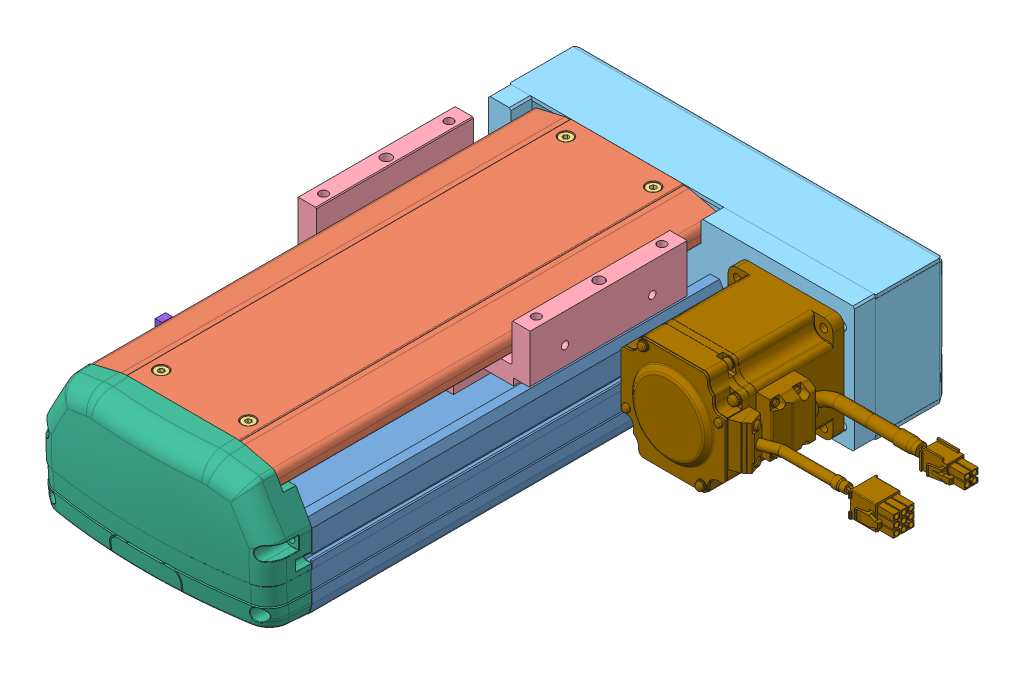
SolidWorks assembly S13-BR-200W, configuration 默认. Lengths in mm.
Overall size (306.2 78 318.96).
14 component instances, 9 part files, 43 mates.
Components (placement in the parent):
- S13-BL底座^S13-BR-200W-1: S13-BL底座^S13-BR-200W [默认] at origin size (135 48 259) (virtual)
- S13-BL上盖^S13-BR-200W-1: S13-BL上盖^S13-BR-200W [默认] at (0 60.45 115.5) size (109 12.5 255) (virtual)
- 内六角圆柱头螺钉M4×8[GB／T70．1-2000]^S13-BR-200W-1: 内六角圆柱头螺钉M4×8[GB／T70．1-2000]^S13-BR-200W [默认] at (-25 72.65 -2) x (0 -1 0) z (-0.993621 0 -0.11277) size (12 7 7) (virtual)
- 内六角圆柱头螺钉M4×8[GB／T70．1-2000]^S13-BR-200W-2: 内六角圆柱头螺钉M4×8[GB／T70．1-2000]^S13-BR-200W [默认] at (25 72.65 -2) x (0 -1 0) z (0.295931 0 -0.955209) size (12 7 7) (virtual)
- 内六角圆柱头螺钉M4×8[GB／T70．1-2000]^S13-BR-200W-3: 内六角圆柱头螺钉M4×8[GB／T70．1-2000]^S13-BR-200W [默认] at (-25 72.65 230) x (0 -1 0) z (0.881053 0 0.473018) size (12 7 7) (virtual)
- 内六角圆柱头螺钉M4×8[GB／T70．1-2000]^S13-BR-200W-4: 内六角圆柱头螺钉M4×8[GB／T70．1-2000]^S13-BR-200W [默认] at (25 72.65 230) x (0 -1 0) z (0.809751 0 0.586773) size (12 7 7) (virtual)
- S13-BC滑座^S13-BR-200W-1: S13-BC滑座^S13-BR-200W [默认] at (-1.3936 35.7784 20) size (133 62 90) (virtual)
- 复件 S13-14-BR电机板罩壳^S13-BR-200W-2: 复件 S13-14-BR电机板罩壳^S13-BR-200W [默认] at (34.6396 24.1 343.3649) x (1 0 0) z (0 1 0) size (210.56 52 72) (virtual)
- 复件 13-14塑胶端盖 ^S13-BR-200W-1: 复件 13-14塑胶端盖 ^S13-BR-200W [默认] at (0 1 256) x (-1 0 0) z (0 0 -1) size (134.5 73.26 31.04) (virtual)
- 复件 外置感应片ST14-17^S13-BR-200W-1: 复件 外置感应片ST14-17^S13-BR-200W [默认] at (-67.5 55 65) x (0 0 1) z (-1 0 0) size (70 30.4 7.7) (virtual)
- 复件 光电开关EE-SX672^S13-BR-200W-1: 复件 光电开关EE-SX672^S13-BR-200W [默认] at (-67.5 19.7 49) x (0 0 1) z (-1 0 0) size (26 25 13) (virtual)
- 复件 光电开关EE-SX672^S13-BR-200W-2: 复件 光电开关EE-SX672^S13-BR-200W [默认] at (-67.5 19.7 75) x (0 0 1) z (-1 0 0) size (26 25 13) (virtual)
- 复件 光电开关EE-SX672^S13-BR-200W-3: 复件 光电开关EE-SX672^S13-BR-200W [默认] at (-67.5 19.7 172) x (0 0 1) z (-1 0 0) size (26 25 13) (virtual)
- 复件 松下200W电机MHMF022L1U22^S13-BR-200W-1: 复件 松下200W电机MHMF022L1U22^S13-BR-200W [默认] at (106.5 35.4 0) x (0 0 -1) z (0 -1 0) size (101 149.2 60) (virtual)
Mates (geometry in assembly coordinates):
- 重合169: coincident: plane of S13-BL上盖^S13-BR-200W-1 through (-25 68.65 -2) normal (0 1 0); plane of 内六角圆柱头螺钉M4×8[GB／T70．1-2000]^S13-BR-200W-1 through (-25.3947 68.65 1.4777) normal (0 -1 0)
- 同心160: concentric: cylinder of 内六角圆柱头螺钉M4×8[GB／T70．1-2000]^S13-BR-200W-1 through (-25 72.65 -2) axis (0 1 0) radius 3.5; cylinder of S13-BL上盖^S13-BR-200W-1 through (-25 68.65 -2) axis (0 1 0) radius 4
- 同心161: concentric: cylinder of 内六角圆柱头螺钉M4×8[GB／T70．1-2000]^S13-BR-200W-2 through (25 72.65 -2) axis (0 1 0) radius 3.5; cylinder of S13-BL上盖^S13-BR-200W-1 through (25 68.65 -2) axis (0 1 0) radius 4
- 重合171: coincident: plane of S13-BL上盖^S13-BR-200W-1 through (25 68.65 -2) normal (0 1 0); circle of 内六角圆柱头螺钉M4×8[GB／T70．1-2000]^S13-BR-200W-2
- 重合189: coincident: plane of S13-BL上盖^S13-BR-200W-1 through (25 68.65 230) normal (0 1 0); plane of 内六角圆柱头螺钉M4×8[GB／T70．1-2000]^S13-BR-200W-4 through (27.0537 68.65 227.1659) normal (0 -1 0)
- 同心192: concentric: cylinder of S13-BL上盖^S13-BR-200W-1 through (25 68.65 230) axis (0 1 0) radius 4; cylinder of 内六角圆柱头螺钉M4×8[GB／T70．1-2000]^S13-BR-200W-4 through (25 72.65 230) axis (0 1 0) radius 2
- 重合190: coincident: plane of S13-BL上盖^S13-BR-200W-1 through (-25 68.65 230) normal (0 1 0); plane of 内六角圆柱头螺钉M4×8[GB／T70．1-2000]^S13-BR-200W-3 through (-23.3444 68.65 226.9163) normal (0 -1 0)
- 同心193: concentric: cylinder of S13-BL上盖^S13-BR-200W-1 through (-25 68.65 230) axis (0 1 0) radius 4; cylinder of 内六角圆柱头螺钉M4×8[GB／T70．1-2000]^S13-BR-200W-3 through (-25 72.65 230) axis (0 1 0) radius 2
- 距离15: distance = 78 mm: plane of S13-BC滑座^S13-BR-200W-1 through (66.5 78 20) normal (0 1 0); plane of S13-BL底座^S13-BR-200W-1 through (-65.3076 0 259) normal (0 -1 0)
- 重合205: coincident: plane of S13-BL底座^S13-BR-200W-1 through (0 0 0) normal (1 0 0); plane of S13-BL上盖^S13-BR-200W-1 through (0 60.45 115.5) normal (1 0 0)
- 距离37: distance = 12 mm: plane of S13-BL底座^S13-BR-200W-1 through (-56.7 26.5 0) normal (0 0 -1); plane of S13-BL上盖^S13-BR-200W-1 through (50.5 64.7864 -12) normal (0 0 -1)
- 重合238: coincident: plane of S13-BL底座^S13-BR-200W-1 through (0 0 0) normal (0 0 1); plane of assembly through (0 0 0) normal (0 0 1)
- 重合239: coincident: plane of S13-BL底座^S13-BR-200W-1 through (0 0 0) normal (0 1 0); plane of assembly through (0 0 0) normal (0 1 0)
- 重合240: coincident: plane of S13-BL底座^S13-BR-200W-1 through (0 0 0) normal (1 0 0); plane of assembly through (0 0 0) normal (1 0 0)
- 宽度2: width: plane of S13-BL底座^S13-BR-200W-1 through (67.5 43.6699 259) normal (1 0 0); plane of S13-BL底座^S13-BR-200W-1 through (-67.5 43.6699 259) normal (-1 0 0); plane of S13-BC滑座^S13-BR-200W-1 through (-66.5 16 113.7559) normal (-1 0 0); plane of S13-BC滑座^S13-BR-200W-1 through (66.5 16 116.3186) normal (1 0 0)
- 重合265: coincident: plane of S13-BL底座^S13-BR-200W-1 through (-56.7 26.5 0) normal (0 0 -1); plane of 复件 S13-14-BR电机板罩壳^S13-BR-200W-2 through (37.5 37 0) normal (0 0 1)
- 重合266: coincident: plane of S13-BL底座^S13-BR-200W-1 through (-67.5 43.6699 259) normal (-1 0 0); plane of 复件 S13-14-BR电机板罩壳^S13-BR-200W-2 through (-67.5 1 0) normal (-1 0 0)
- 距离47: distance = 1 mm: plane of 复件 S13-14-BR电机板罩壳^S13-BR-200W-2 through (-67.5 1 0) normal (0 -1 0); plane of S13-BL底座^S13-BR-200W-1 through (-65.3076 0 259) normal (0 -1 0)
- 重合269: coincident: plane of S13-BL上盖^S13-BR-200W-1 through (-54 60.45 243) normal (0 -1 0); plane of 复件 S13-14-BR电机板罩壳^S13-BR-200W-2 through (-54.5 60.45 -12) normal (0 1 0)
- 同心202: concentric: cylinder of S13-BL底座^S13-BR-200W-1 through (62.5 39.5 259) axis (0 0 -1) radius 1.4999; cylinder of 复件 13-14塑胶端盖 ^S13-BR-200W-1 through (62.5 39.5 236) axis (0 0 -1) radius 2.1
- 同心203: concentric: cylinder of S13-BL底座^S13-BR-200W-1 through (-62.5 39.5 259) axis (0 0 -1) radius 1.5; cylinder of 复件 13-14塑胶端盖 ^S13-BR-200W-1 through (-62.5 39.5 236) axis (0 0 -1) radius 2.1
- 重合270: coincident: plane of S13-BL底座^S13-BR-200W-1 through (-73.9407 48 236) normal (0 0 1); plane of 复件 13-14塑胶端盖 ^S13-BR-200W-1 through (0 1 236) normal (0 0 1)
- 重合271: coincident: plane of S13-BC滑座^S13-BR-200W-1 through (-66.5 16 113.7559) normal (-1 0 0); plane of 复件 外置感应片ST14-17^S13-BR-200W-1 through (-66.5 55 65) normal (1 0 0)
- 同心204: concentric: cylinder of S13-BC滑座^S13-BR-200W-1 through (-67 61 94) axis (-1 0 0) radius 2.1; cylinder of 复件 外置感应片ST14-17^S13-BR-200W-1 through (-67.5 61 94) axis (-1 0 0) radius 2.55
- 同心205: concentric: cylinder of S13-BC滑座^S13-BR-200W-1 through (-67 61 44) axis (-1 0 0) radius 2.1; cylinder of 复件 外置感应片ST14-17^S13-BR-200W-1 through (-67.5 61 44) axis (-1 0 0) radius 2.55
- 重合272: coincident: plane of S13-BL底座^S13-BR-200W-1 through (-67.5 43.6699 259) normal (-1 0 0); plane of 复件 光电开关EE-SX672^S13-BR-200W-1 through (-67.5 44.7 49) normal (1 0 0)
- 距离49: distance = 19.7 mm: plane of 复件 光电开关EE-SX672^S13-BR-200W-1 through (-80.5 19.7 49) normal (0 -1 0); plane of S13-BL底座^S13-BR-200W-1 through (-65.3076 0 259) normal (0 -1 0)
- 距离50: distance = 53 mm: plane of 复件 光电开关EE-SX672^S13-BR-200W-1 through (-80.5 19.7 53) normal (0 0 -1); plane of S13-BL底座^S13-BR-200W-1 through (-56.7 26.5 0) normal (0 0 -1)
- 重合275: coincident: plane of 复件 光电开关EE-SX672^S13-BR-200W-1 through (-80.5 44.7 49) normal (-1 0 0); plane of 复件 光电开关EE-SX672^S13-BR-200W-2 through (-80.5 44.7 75) normal (-1 0 0)
- 重合276: coincident: plane of 复件 光电开关EE-SX672^S13-BR-200W-1 through (-70 32.7 65) normal (0 0 1); plane of 复件 光电开关EE-SX672^S13-BR-200W-2 through (-70 32.7 65) normal (0 0 -1)
- 重合277: coincident: plane of 复件 光电开关EE-SX672^S13-BR-200W-1 through (-80.5 19.7 49) normal (0 -1 0); plane of 复件 光电开关EE-SX672^S13-BR-200W-2 through (-80.5 19.7 75) normal (0 -1 0)
- 宽度4: width: plane of 复件 光电开关EE-SX672^S13-BR-200W-2 through (-80.5 19.7 79) normal (0 0 -1); plane of 复件 光电开关EE-SX672^S13-BR-200W-1 through (-80.5 19.7 59) normal (0 0 1); plane of 复件 外置感应片ST14-17^S13-BR-200W-1 through (-74.2 37.6 61.5) normal (0 0 -1); plane of 复件 外置感应片ST14-17^S13-BR-200W-1 through (-74.2 53 76.5) normal (0 0 1)
- 重合278: coincident: plane of 复件 光电开关EE-SX672^S13-BR-200W-2 through (-80.5 44.7 75) normal (-1 0 0); plane of 复件 光电开关EE-SX672^S13-BR-200W-3 through (-80.5 44.7 172) normal (-1 0 0)
- 重合279: coincident: plane of 复件 光电开关EE-SX672^S13-BR-200W-2 through (-80.5 19.7 75) normal (0 -1 0); plane of 复件 光电开关EE-SX672^S13-BR-200W-3 through (-80.5 19.7 172) normal (0 -1 0)
- 距离51: distance = 58 mm: plane of 复件 光电开关EE-SX672^S13-BR-200W-3 through (-80.5 19.7 178) normal (0 0 1); plane of S13-BL底座^S13-BR-200W-1 through (-73.9407 48 236) normal (0 0 1)
- 宽度5: width: plane of 复件 S13-14-BR电机板罩壳^S13-BR-200W-2 through (103.5 60.4 -12) normal (0 -1 0); plane of 复件 S13-14-BR电机板罩壳^S13-BR-200W-2 through (103.5 10.4 -12) normal (0 1 0); cylinder of 复件 松下200W电机MHMF022L1U22^S13-BR-200W-1 through (106.5 35.4 -30) axis (0 0 1) radius 5.5
- 重合281: coincident: plane of 复件 S13-14-BR电机板罩壳^S13-BR-200W-2 through (37.5 37 0) normal (0 0 1); plane of 复件 松下200W电机MHMF022L1U22^S13-BR-200W-1 through (131.5 10.4 0) normal (0 0 -1)
- 距离52: distance = 30 mm: plane of 复件 松下200W电机MHMF022L1U22^S13-BR-200W-1 through (136.5 60.4 54.5) normal (1 0 0); moEndPointRef_w of 复件 S13-14-BR电机板罩壳^S13-BR-200W-2
- 平行1: parallel: plane of 复件 S13-14-BR电机板罩壳^S13-BR-200W-2 through (142.5 1 0) normal (1 0 0); plane of 复件 松下200W电机MHMF022L1U22^S13-BR-200W-1 through (136.5 60.4 54.5) normal (1 0 0)
- 距离53: distance = 117 mm: plane of 复件 S13-14-BR电机板罩壳^S13-BR-200W-2 through (37.5 37 -52) normal (0 0 -1); cylinder of S13-BC滑座^S13-BR-200W-1 through (-61 78 65) axis (0 1 0) radius 3
- 同心206: concentric: cylinder of S13-BC滑座^S13-BR-200W-1 through (-67 61 90) axis (-1 0 0) radius 2.1; cylinder of 复件 外置感应片ST14-17^S13-BR-200W-1 through (-67.5 61 90) axis (-1 0 0) radius 2.55
- 同心207: concentric: cylinder of S13-BC滑座^S13-BR-200W-1 through (-67 61 40) axis (-1 0 0) radius 2.1; cylinder of 复件 外置感应片ST14-17^S13-BR-200W-1 through (-67.5 61 40) axis (-1 0 0) radius 2.55
- 宽度6: width: plane of 复件 光电开关EE-SX672^S13-BR-200W-1 through (-80.5 19.7 55) normal (0 0 1); plane of 复件 光电开关EE-SX672^S13-BR-200W-2 through (-80.5 19.7 75) normal (0 0 -1); plane of 复件 外置感应片ST14-17^S13-BR-200W-1 through (-74.2 53 72.5) normal (0 0 1); plane of 复件 外置感应片ST14-17^S13-BR-200W-1 through (-74.2 37.6 57.5) normal (0 0 -1)
